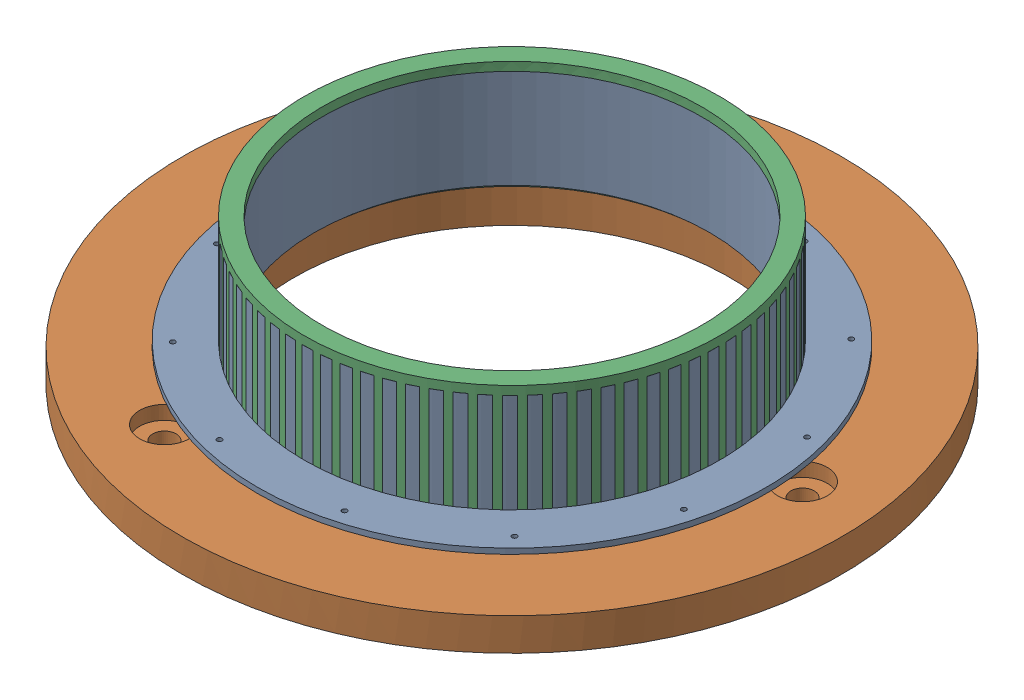
SolidWorks assembly MotorRetention_Assem, configuration Default. Lengths in mm.
Overall size (139.98 31.26 139.98).
3 component instances, 3 part files, 4 mates.
Components (placement in the parent):
- MotorRetention_Lower-1: MotorRetention_Lower [Default] at (-62.0752 2.8933 23.9492) size (98.06 20.14 98.06)
- ThrustPlate-1: ThrustPlate [Default] at (-62.0752 -6.5567 23.9492) x (0.108046 0 0.994146) z (-0.994146 0 0.108046) size (127 9.45 127)
- MotorRetention_Upper-1: MotorRetention_Upper [Default] at (-62.0752 2.0833 23.9492) x (0.674096 0 -0.738643) z (0.738643 0 0.674096) size (80.01 22.62 80.01)
Mates (geometry in assembly coordinates):
- Concentric1: concentric aligned: circle of MotorLower-1; circle of ThrustPlate-1
- Coincident4: coincident anti-aligned: plane of MotorRetention_Lower-1 through (-62.0752 2.8933 23.9492) normal (0 -1 0); plane of ThrustPlate-1 through (-62.0752 2.8933 23.9492) normal (0 1 0)
- Concentric2: concentric anti-aligned: circle of MotorLower-1; circle of MotorRetention_Upper-1
- Coincident6: coincident anti-aligned: plane of MotorRetention_Lower-1 through (-62.0752 23.0333 23.9492) normal (0 1 0); plane of MotorRetention_Upper-1 through (-62.0752 23.0333 23.9492) normal (0 -1 0)
